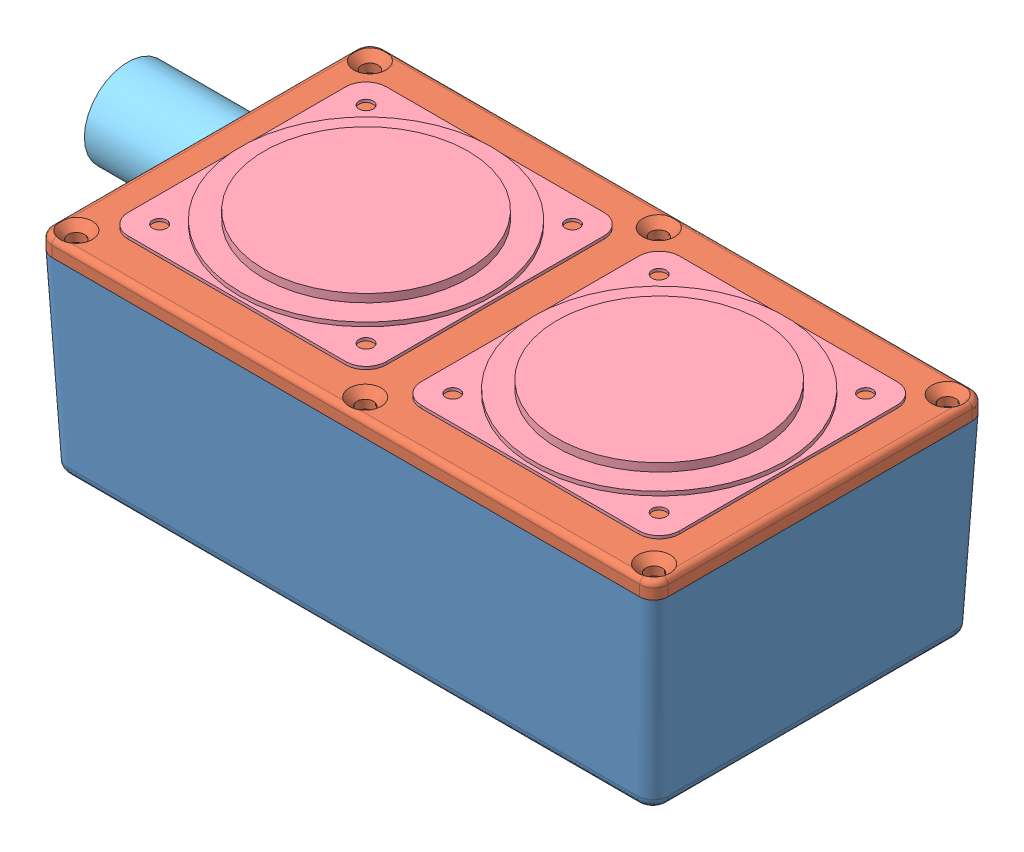
SolidWorks assembly Assem1, configuration Default. Lengths in mm.
Overall size (195.87 54.5 82.01).
6 component instances, 5 part files, 17 mates.
Components (placement in the parent):
- box-2: box [Default] at (37.0534 62.8371 138.3127) size (152.01 46.81 82.01)
- box-cover-2: box-cover [Default] at (37.0534 109.6371 138.3127) size (152 4.24 82)
- Radiator-1: Radiator [Default] at (37.0534 65.1371 138.3127) size (85 7.9 58.5)
- speaker-1: speaker [Default] at (0.9034 114.3371 138.1627) x (-1 0 0) z (0 0 1) size (66.57 33.7 63.7)
- speaker-2: speaker [Default] at (73.2034 114.3371 138.1627) x (0 0 1) z (1 0 0) size (66.57 33.7 63.7)
- battery-cover-1: battery-cover [Default] at (-82.8085 83.9016 113.183) size (90.43 21.5 21.5)
Mates (geometry in assembly coordinates):
- Parallel1: parallel aligned: line of box-2 through (113.0534 109.6371 175.8127) axis (0 0 -1); line of box-cover-2 through (113.0534 109.6371 175.8127) axis (0 0 -1)
- Parallel2: parallel aligned: line of box-2 through (-35.4466 109.6371 179.3127) axis (1 0 0); line of box-cover-2 through (-35.4466 109.6371 179.3127) axis (1 0 0)
- Coincident9: coincident: plane of box-2 through (37.0534 65.1371 173.8627) normal (0 1 0); plane of Radiator-1 through (7.9191 65.1371 160.7247) normal (0 -1 0)
- Distance1: distance = 0 mm: point of Radiator-1; point of box-2
- Coincident13: coincident: point of Radiator-1; plane of box-2
- Coincident14: coincident: point of Radiator-1; plane of box-2
- Coincident20: coincident: line of box-2 through (37.0534 62.8371 138.3127) axis (0 1 0); point of box-cover-2
- Parallel3: parallel aligned: plane of box-cover-2 through (109.5534 113.6371 179.3127) normal (0 0 1); plane of speaker-1 through (-25.9466 113.6371 170.0127) normal (0 0 1)
- Parallel4: parallel aligned: plane of box-cover-2 through (109.5534 113.6371 179.3127) normal (0 0 1); plane of speaker-2 through (100.0534 113.6371 170.0127) normal (0 0 1)
- Parallel5: parallel anti-aligned: line of box-cover-2 through (-35.4466 109.6371 179.3127) axis (1 0 0); line of speaker-1 through (27.7534 113.6371 170.0127) axis (-1 0 0)
- Parallel6: parallel anti-aligned: line of box-cover-2 through (-35.4466 109.6371 179.3127) axis (1 0 0); line of speaker-2 through (100.0534 113.6371 170.0127) axis (-1 0 0)
- Distance2: distance = 8 mm aligned: plane of speaker-2 through (105.0534 113.6371 165.0127) normal (1 0 0); plane of box-cover-2 through (113.0534 113.6371 175.8127) normal (1 0 0)
- Distance3: distance = 8 mm aligned: plane of speaker-1 through (-30.9466 113.6371 165.0127) normal (-1 0 0); plane of box-cover-2 through (-38.9466 113.6371 175.8127) normal (-1 0 0)
- Distance4: distance = 9 mm aligned: plane of speaker-1 through (-25.9466 113.6371 106.3127) normal (0 0 -1); plane of box-cover-2 through (109.5534 113.6371 97.3127) normal (0 0 -1)
- Distance5: distance = 9 mm aligned: plane of speaker-2 through (100.0534 113.6371 106.3127) normal (0 0 -1); plane of box-cover-2 through (109.5534 113.6371 97.3127) normal (0 0 -1)
- Coincident21: coincident anti-aligned: plane of box-cover-2 through (-35.4466 113.6371 175.8127) normal (0 1 0); plane of speaker-1 through (27.7534 113.6371 165.0127) normal (0 -1 0)
- Coincident22: coincident anti-aligned: plane of box-cover-2 through (-35.4466 113.6371 175.8127) normal (0 1 0); plane of speaker-2 through (100.0534 113.6371 111.3127) normal (0 -1 0)
